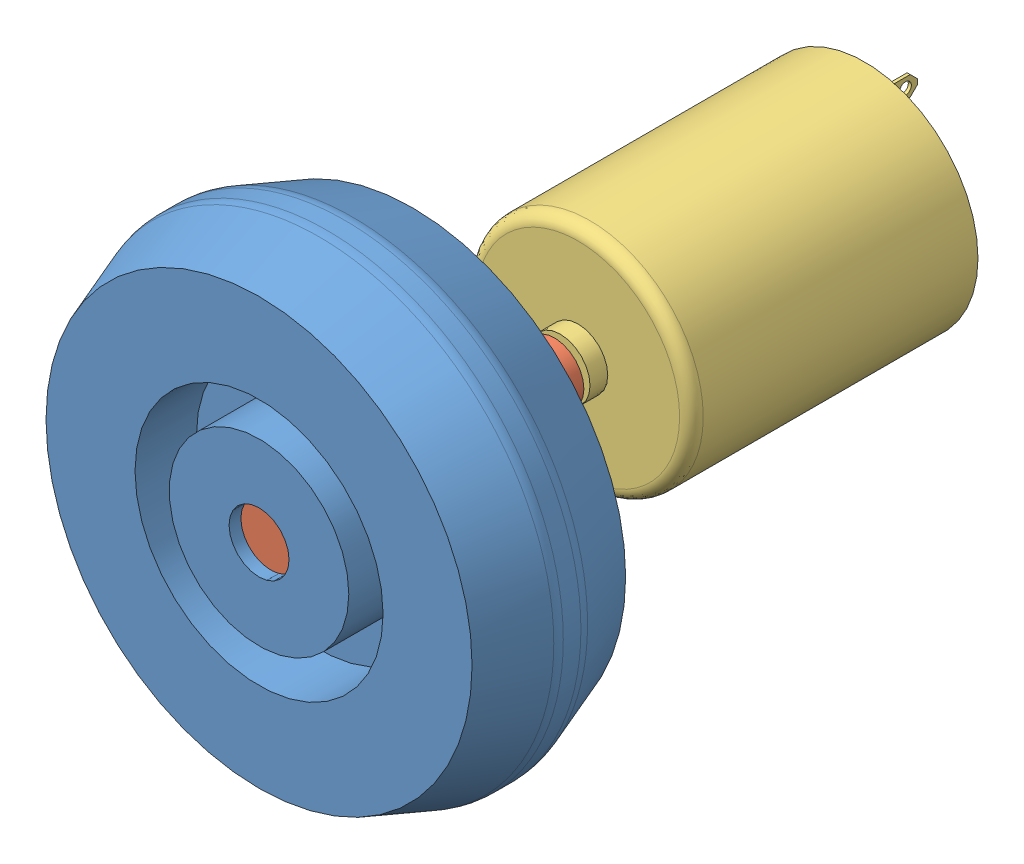
SolidWorks assembly MotorWheelASM, configuration Default. Lengths in mm.
Overall size (50.8 50.8 69.16).
11 component instances, 5 part files, 8 mates.
Components (placement in the parent):
- Omni_Wheel-1: Omni_Wheel [Default] at (-0.5626 28.5849 47.8869) size (50.8 50.8 16.51)
- MotorWheelCoupler-1: MotorWheelCoupler [Default] at (-0.5626 28.5849 37.0919) size (19.05 19.05 30.48)
- DC_Motor-1: DC_Motor [Default] at (-0.5626 28.5849 -8.9583) size (24.38 24.38 45.03)
- 92311A050_18-8 SS CUP POINT SET SCREW-1: 92311A050_18-8 SS CUP POINT SET SCREW [92311A050] at (-2.3871 28.5849 26.9319) x (0 0 1) z (-1 0 0) size (1.76 1.55 1.71)
- 92311A050_18-8 SS CUP POINT SET SCREW-2: 92311A050_18-8 SS CUP POINT SET SCREW [92311A050] at (-0.5626 26.7604 26.9319) x (0 0 1) z (0 -1 0) size (1.76 1.55 1.71)
- 92311A050_18-8 SS CUP POINT SET SCREW-3: 92311A050_18-8 SS CUP POINT SET SCREW [92311A050] at (1.2619 28.5849 26.9319) x (0 0 1) z (1 0 0) size (1.76 1.55 1.71)
- 92311A050_18-8 SS CUP POINT SET SCREW-4: 92311A050_18-8 SS CUP POINT SET SCREW [92311A050] at (-0.5626 30.4094 26.9319) x (0 0 1) z (0 1 0) size (1.76 1.55 1.71)
- 94629A550_THREAD-CUTTING SCREW FOR SOFT PLASTICS-1: 94629A550_THREAD-CUTTING SCREW FOR SOFT PLASTICS [94629A550] at (4.0094 24.0129 37.0919) x (-0.923728 -0.383049 0) z (0 0 -1) size (5.56 5.82 14.35)
- 94629A550_THREAD-CUTTING SCREW FOR SOFT PLASTICS-2: 94629A550_THREAD-CUTTING SCREW FOR SOFT PLASTICS [94629A550] at (4.0094 33.1569 37.0919) x (0.383049 -0.923728 0) z (0 0 -1) size (5.56 5.82 14.35)
- 94629A550_THREAD-CUTTING SCREW FOR SOFT PLASTICS-3: 94629A550_THREAD-CUTTING SCREW FOR SOFT PLASTICS [94629A550] at (-5.1346 33.1569 37.0919) x (0.923728 0.383049 0) z (0 0 -1) size (5.56 5.82 14.35)
- 94629A550_THREAD-CUTTING SCREW FOR SOFT PLASTICS-4: 94629A550_THREAD-CUTTING SCREW FOR SOFT PLASTICS [94629A550] at (-5.1346 24.0129 37.0919) x (-0.383049 0.923728 0) z (0 0 -1) size (5.56 5.82 14.35)
Mates (geometry in assembly coordinates):
- Concentric1: concentric anti-aligned: cylinder of Omni_Wheel-1 through (-0.5626 28.5849 39.6319) axis (0 0 1) radius 3.2258; cylinder of MotorWheelCoupler-1 through (-0.5626 28.5849 54.8719) axis (0 0 -1) radius 3.2258
- Coincident1: coincident anti-aligned: plane of Omni_Wheel-1 through (-0.5626 28.5849 39.6319) normal (0 0 -1); plane of MotorWheelCoupler-1 through (-0.5626 28.5849 39.6319) normal (0 0 1)
- Concentric5: concentric aligned: cylinder of MotorWheelCoupler-1 through (-3.7376 28.5849 26.9319) axis (-1 0 0) radius 0.5956; line of 92311A050_18-8 SS CUP POINT SET SCREW-1 through (-1.7188 28.5849 26.9319) axis (-1 0 0)
- Coincident4: coincident: cylinder of DC_Motor-1 through (-0.5626 28.5849 32.0119) axis (0 0 -1) radius 0.9969; point of 92311A050_18-8 SS CUP POINT SET SCREW-1
- Coincident5: coincident anti-aligned: plane of MotorWheelCoupler-1 through (-0.5626 28.5849 37.0919) normal (0 0 -1); plane of 94629A550_THREAD-CUTTING SCREW FOR SOFT PLASTICS-1 through (4.0094 24.0129 37.0919) normal (0 0 1)
- Concentric6: concentric anti-aligned: cylinder of MotorWheelCoupler-1 through (4.0094 24.0129 37.0919) axis (0 0 -1) radius 1.632; cylinder of 94629A550_THREAD-CUTTING SCREW FOR SOFT PLASTICS-1 through (4.0094 24.0129 37.5879) axis (0 0 1) radius 1.4224
- Concentric7: concentric aligned: cylinder of MotorWheelCoupler-1 through (-0.5626 28.5849 24.3919) axis (0 0 -1) radius 0.9969; cylinder of DC_Motor-1 through (-0.5626 28.5849 32.0119) axis (0 0 -1) radius 0.9969
- Distance1: distance = 0.635 mm anti-aligned: plane of MotorWheelCoupler-1 through (-0.5626 28.5849 24.3919) normal (0 0 -1); plane of DC_Motor-1 through (-0.5626 28.5849 23.7569) normal (0 0 1)
